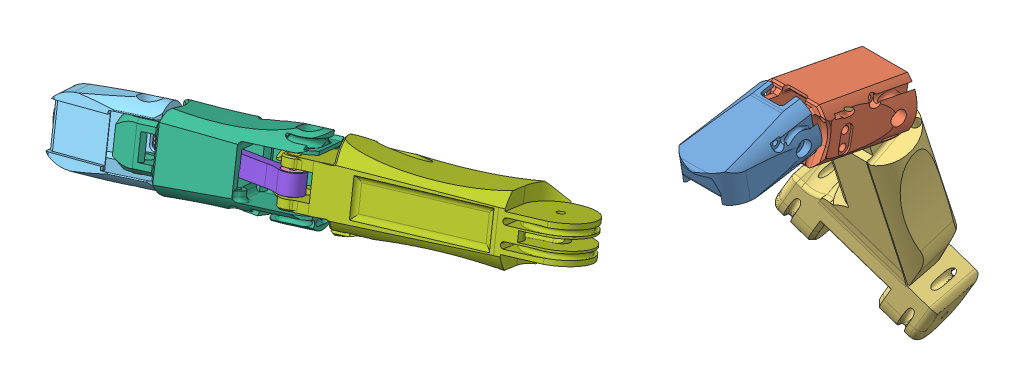
SolidWorks assembly assembly thumb finger, configuration Default. Lengths in mm.
Overall size (220.97 100.12 94.88).
20 component instances, 8 part files, 13 mates.
Components (placement in the parent):
- thumb link1-1: thumb link1 [Default] at (0 -77.0447 -15.9856) x (1 0 0) z (0 -0.98608 -0.166274) size (19.61 27.22 13.31)
- thumb link2-1: thumb link2 [Default] at (0 -82.0661 -42.0768) x (1 0 0) z (0 -0.98198 0.188986) size (22.18 36.65 15.24)
- thumb link3-1: thumb link3 [Default] at (-32.4409 -125.804 -58.5912) x (0.85264 -0.497728 -0.15897) z (0.15897 -0.042709 0.986359) size (45.65 61.19 26.37)
- bearing 1.5-4-5-2-1: bearing 1.5-4-5-2 [Default] at (-4.348 -82.0661 -42.0768) x (0 0.304385 0.952549) z (0 -0.952549 0.304385) size (5 2 5)
- bearing 1.5-4-5-2-2: bearing 1.5-4-5-2 [Default] at (4.348 -82.0661 -42.0768) x (0 0.868282 -0.49607) z (0 -0.49607 -0.868282) size (5 2 5)
- bearing 1.5-4-5-2-3: bearing 1.5-4-5-2 [Default] at (-4.35 -77.0447 -15.9856) x (0 0.304385 0.952549) z (0 -0.952549 0.304385) size (5 2 5)
- bearing 1.5-4-5-2-4: bearing 1.5-4-5-2 [Default] at (4.35 -77.0447 -15.9856) x (0 0.868282 -0.49607) z (0 -0.49607 -0.868282) size (5 2 5)
- assembly middle finger-1: assembly middle finger [Default] at (-168.3727 -136.3434 44.4353) x (-0.173132 0.932727 -0.3163) z (0.262103 0.353203 0.898081) size (26.12 124.19 19.82)
  - middle link1-2: middle link1 [Default] at (0 -22.0125 -35.7101) x (1 0 0) z (0 -0.067342 0.99773) size (19.5 27.22 13.31)
  - middle link2-2: middle link2 [Default] at (0 -57.5994 -36.9948) x (1 0 0) z (0 -0.036077 0.999349) size (23.01 45.61 15.34)
  - middle link3-1: middle link3 [Default] at (0 -115.2194 -36.9948) size (26.12 70.93 19.35)
  - middle linkage-1: middle linkage [Default] at (0 -39.6096 -36.4016) x (1 0 0) z (0 0.999451 0.033137) size (5 17.7 38.56)
  - bearing 1.5-4-5-2-3: bearing 1.5-4-5-2 [Default] at (4.35 -57.5994 -36.9948) x (0 -0.484483 0.8748) z (0 0.8748 0.484483) size (5 2 5)
  - bearing 1.5-4-5-2-4: bearing 1.5-4-5-2 [Default] at (0.5 -57.5994 -31.1248) x (0 -0.673592 0.739103) z (0 0.739103 0.673592) size (5 2 5)
  - bearing 1.5-4-5-2-5: bearing 1.5-4-5-2 [Default] at (-4.35 -57.5994 -36.9948) x (0 0.90845 0.417993) z (0 -0.417993 0.90845) size (5 2 5)
  - bearing 1.5-4-5-2-6: bearing 1.5-4-5-2 [Default] at (-0.5 -57.5994 -31.1248) x (0 0.90845 0.417993) z (0 -0.417993 0.90845) size (5 2 5)
  - bearing 1.5-4-5-2-9: bearing 1.5-4-5-2 [Default] at (-0.5 -24.8761 -41.5454) x (0 0.90845 0.417993) z (0 -0.417993 0.90845) size (5 2 5)
  - bearing 1.5-4-5-2-10: bearing 1.5-4-5-2 [Default] at (0.5 -24.8761 -41.5454) x (0 -0.673592 0.739103) z (0 0.739103 0.673592) size (5 2 5)
  - bearing 1.5-4-5-2-11: bearing 1.5-4-5-2 [Default] at (-4.35 -22.0125 -35.7101) x (0 0.90845 0.417993) z (0 -0.417993 0.90845) size (5 2 5)
  - bearing 1.5-4-5-2-12: bearing 1.5-4-5-2 [Default] at (4.35 -22.0125 -35.7101) x (0 -0.673592 0.739103) z (0 0.739103 0.673592) size (5 2 5)
Mates (geometry in assembly coordinates):
- Concentric1: concentric: cylinder of assembly; cylinder of assembly; cylinder of thumb link2-1 through (7.4 -82.0661 -42.0768) axis (1 0 0) radius 2; cylinder of thumb link3-1 through (-5.748 -82.0661 -42.0768) axis (1 0 0) radius 2.55
- Width1: width: plane of assembly; plane of assembly; plane of assembly; plane of assembly; plane of thumb link2-1 through (-6.4 -74.1862 -33.4098) normal (1 0 0); plane of thumb link2-1 through (6.4 -74.1862 -33.4098) normal (-1 0 0); plane of thumb link3-1 through (-5.748 -125.804 -58.5912) normal (-1 0 0); plane of thumb link3-1 through (5.748 -125.804 -58.5912) normal (1 0 0)
- Concentric2: concentric: cylinder of assembly; cylinder of assembly; cylinder of thumb link1-1 through (7.3 -77.0447 -15.9856) axis (1 0 0) radius 2.05; cylinder of thumb link2-1 through (-10.4 -77.0447 -15.9856) axis (1 0 0) radius 2.575
- Width2: width: plane of assembly; plane of assembly; plane of assembly; plane of assembly; plane of thumb link1-1 through (-6.4 -81.8542 12.5368) normal (1 0 0); plane of thumb link1-1 through (6.4 -81.8542 12.5368) normal (-1 0 0); plane of thumb link2-1 through (-5.75 -78.0464 -21.1901) normal (-1 0 0); plane of thumb link2-1 through (5.75 -78.0464 -21.1901) normal (1 0 0)
- Coincident1: coincident: plane of assembly through (0 0 0) normal (1 0 0); plane of thumb link2-1 through (0 -82.0661 -42.0768) normal (1 0 0); plane of assembly
- Concentric4: concentric: cylinder of assembly; cylinder of assembly; cylinder of thumb link3-1 through (-5.748 -82.0661 -42.0768) axis (1 0 0) radius 2.55; cylinder of bearing 1.5-4-5-2-1 through (-6.348 -82.0661 -42.0768) axis (1 0 0) radius 2
- Coincident2: coincident: plane of assembly; plane of assembly; plane of thumb link3-1 through (-5.748 -125.804 -58.5912) normal (-1 0 0); plane of bearing 1.5-4-5-2-1 through (-5.748 -82.0661 -42.0768) normal (1 0 0)
- Concentric5: concentric: cylinder of assembly; cylinder of assembly; cylinder of thumb link3-1 through (-5.748 -82.0661 -42.0768) axis (1 0 0) radius 2.55; cylinder of bearing 1.5-4-5-2-2 through (6.348 -82.0661 -42.0768) axis (-1 0 0) radius 2
- Coincident3: coincident: plane of assembly; plane of assembly; plane of thumb link3-1 through (5.748 -125.804 -58.5912) normal (1 0 0); plane of bearing 1.5-4-5-2-2 through (5.748 -82.0661 -42.0768) normal (-1 0 0)
- Concentric6: concentric: cylinder of assembly; cylinder of assembly; cylinder of thumb link2-1 through (-10.4 -77.0447 -15.9856) axis (1 0 0) radius 2.575; cylinder of bearing 1.5-4-5-2-4 through (6.35 -77.0447 -15.9856) axis (-1 0 0) radius 2
- Coincident4: coincident: plane of assembly; plane of assembly; plane of thumb link2-1 through (5.75 -78.0464 -21.1901) normal (1 0 0); plane of bearing 1.5-4-5-2-4 through (5.75 -77.0447 -15.9856) normal (-1 0 0)
- Concentric7: concentric: cylinder of assembly; cylinder of assembly; cylinder of thumb link2-1 through (-10.4 -77.0447 -15.9856) axis (1 0 0) radius 2.575; cylinder of bearing 1.5-4-5-2-3 through (-6.35 -77.0447 -15.9856) axis (1 0 0) radius 2
- Coincident5: coincident: plane of assembly; plane of assembly; plane of thumb link2-1 through (-5.75 -78.0464 -21.1901) normal (-1 0 0); plane of bearing 1.5-4-5-2-3 through (-5.75 -77.0447 -15.9856) normal (1 0 0)
